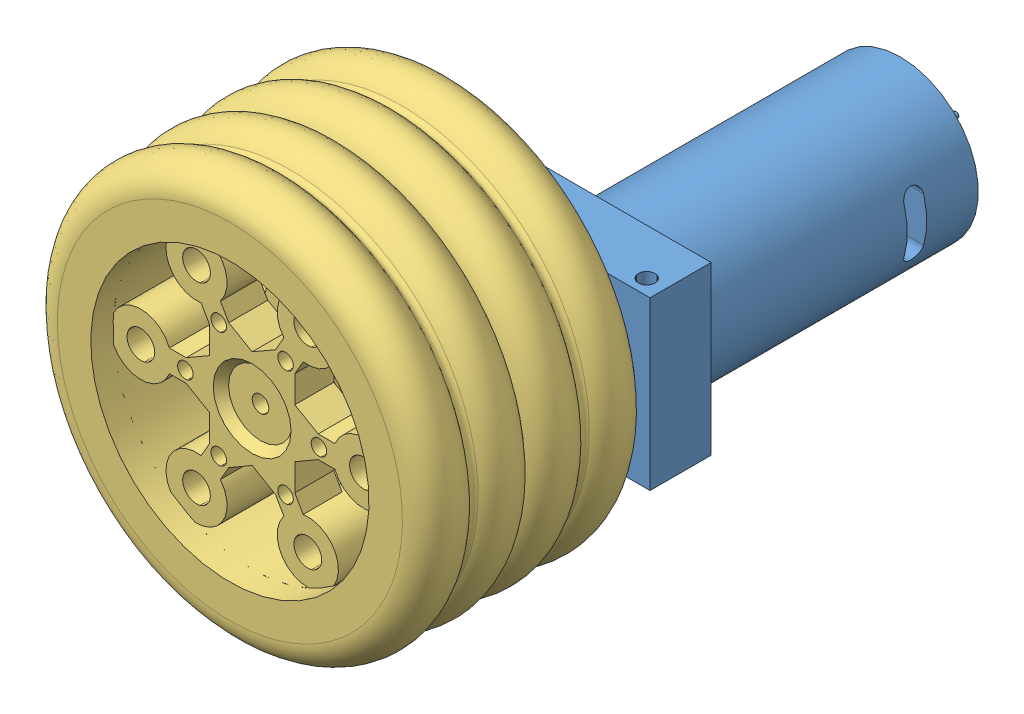
SolidWorks assembly 轮, configuration 默认. Lengths in mm.
Overall size (98.35 98.35 113).
4 component instances, 3 part files, 9 mates.
Components (placement in the parent):
- 电机-1: 电机 [默认] at (84.5138 -145.3601 99.0444) x (-1 0 0) z (0 1 0) size (47 82 30)
- 联轴器-1: 联轴器 [默认] at (51.0138 -130.3601 124.0444) x (0 0 -1) z (1 0 0) size (10 12 13.86)
- 轮子-1: 轮子 [默认] at (51.0138 -130.3601 122.0444) x (0.866025 0.5 0) z (0 0 1) size (72 72 20)
- 轮子-2: 轮子 [默认] at (51.0138 -130.3601 142.0444) x (0.866025 0.5 0) z (0 0 1) size (72 72 20)
Mates (geometry in assembly coordinates):
- 重合1: coincident anti-aligned: plane of 联轴器-1 through (47.5497 -124.3601 114.0444) normal (0 1 0); plane of 轮子-1 through (47.5497 -124.3601 124.0444) normal (0 -1 0)
- 重合2: coincident anti-aligned: plane of 联轴器-1 through (54.4779 -124.3601 114.0444) normal (0.866025 0.5 0); plane of 轮子-1 through (54.4779 -124.3601 124.0444) normal (-0.866025 -0.5 0)
- 重合3: coincident anti-aligned: plane of 联轴器-1 through (51.0138 -130.3601 124.0444) normal (0 0 1); plane of 轮子-1 through (51.0138 -130.3601 124.0444) normal (0 0 -1)
- 重合4: coincident anti-aligned: plane of 电机-1 through (54.7666 -130.3601 121.0444) normal (0.866025 0.5 0); plane of 联轴器-1 through (52.8902 -127.1101 121.0444) normal (-0.866025 -0.5 0)
- 重合5: coincident anti-aligned: plane of 电机-1 through (52.8902 -127.1101 121.0444) normal (0 1 0); plane of 联轴器-1 through (49.1375 -127.1101 121.0444) normal (0 -1 0)
- 重合6: coincident anti-aligned: plane of 电机-1 through (84.5138 -145.3601 121.0444) normal (0 0 1); plane of 联轴器-1 through (51.0138 -130.3601 121.0444) normal (0 0 -1)
- 重合7: coincident anti-aligned: plane of 轮子-1 through (72.6645 -117.8601 132.0444) normal (0 0 1); plane of 轮子-2 through (72.6645 -117.8601 132.0444) normal (0 0 -1)
- 同心1: concentric aligned: cylinder of 轮子-1 through (51.0138 -130.3601 112.0444) axis (0 0 1) radius 1.5; cylinder of 轮子-2 through (51.0138 -130.3601 132.0444) axis (0 0 1) radius 1.5
- 同心2: concentric aligned: cylinder of 轮子-1 through (31.0138 -130.3601 112.0444) axis (0 0 1) radius 2.5; cylinder of 轮子-2 through (31.0138 -130.3601 132.0444) axis (0 0 1) radius 2.5
